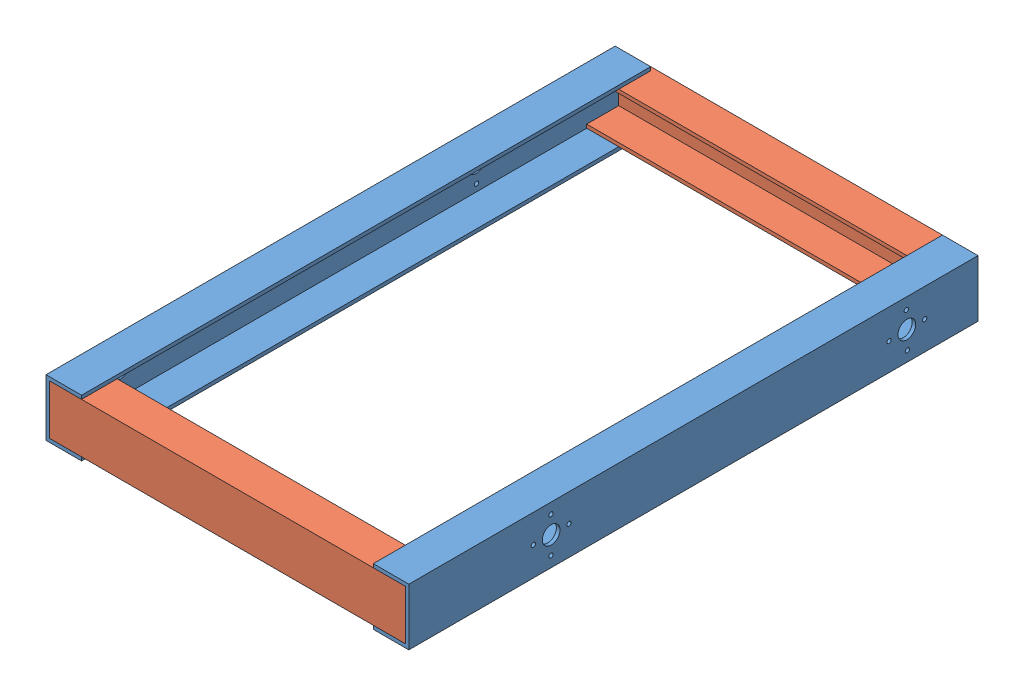
SolidWorks assembly Assem2, configuration Default. Lengths in mm.
Overall size (510 80 805).
4 component instances, 2 part files, 8 mates.
Components (placement in the parent):
- C_Section_800-1: C_Section_800 [Default] at (175.9878 416.6284 678.2773) size (50 80 800)
- C_Section_Back-1: C_Section_Back [Default] at (404.8211 401.1182 289.318) size (500 70 50)
- C_Section_Back-2: C_Section_Back [Default] at (404.8211 401.1182 1062.2367) x (-1 0 0) z (0 0 -1) size (500 70 50)
- C_Section_800-2: C_Section_800 [Default] at (633.6544 416.6284 678.2773) x (-1 0 0) z (0 0 -1) size (50 80 800)
Mates (geometry in assembly coordinates):
- Coincident2: coincident: line of assembly; line of assembly; line of C_Section_800-1 through (154.8211 384.1284 1078.2773) axis (0 0 -1); line of C_Section_Back-2 through (154.8211 384.1284 1028.2773) axis (0 0 1)
- Coincident3: coincident: plane of assembly; plane of assembly; plane of C_Section_800-1 through (199.8211 384.1284 1078.2773) normal (0 1 0); plane of C_Section_Back-2 through (154.8211 384.1284 1078.2773) normal (0 -1 0)
- Coincident4: coincident: line of assembly; line of assembly; line of C_Section_800-1 through (154.8211 384.1284 1078.2773) axis (0 1 0); line of C_Section_Back-2 through (154.8211 384.1284 1078.2773) axis (0 1 0)
- Coincident5: coincident: line of assembly; line of assembly; line of C_Section_800-1 through (154.8211 384.1284 278.2773) axis (0 1 0); line of C_Section_Back-1 through (154.8211 449.1284 278.2773) axis (0 -1 0)
- Coincident6: coincident: plane of assembly; plane of assembly; plane of C_Section_800-1 through (199.8211 384.1284 1078.2773) normal (0 1 0); plane of C_Section_Back-1 through (654.8211 384.1284 273.2773) normal (0 -1 0)
- Coincident8: coincident: plane of assembly; plane of assembly; plane of C_Section_Back-2 through (154.8211 384.1284 1078.2773) normal (0 -1 0); plane of C_Section_800-2 through (609.8211 384.1284 278.2773) normal (0 1 0)
- Coincident9: coincident: line of assembly; line of assembly; line of C_Section_Back-2 through (654.8211 384.1284 1028.2773) axis (0 0 1); line of C_Section_800-2 through (654.8211 384.1284 278.2773) axis (0 0 1)
- Coincident10: coincident: line of assembly; line of assembly; line of C_Section_Back-2 through (654.8211 384.1284 1078.2773) axis (0 1 0); line of C_Section_800-2 through (654.8211 384.1284 1078.2773) axis (0 1 0)
